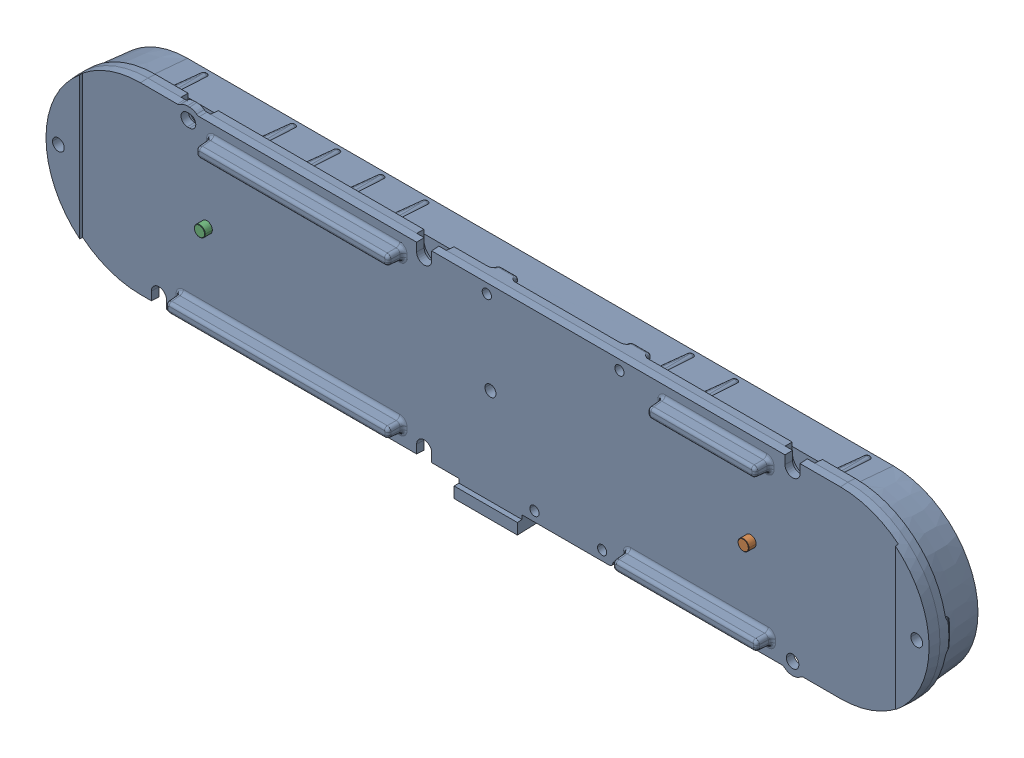
SolidWorks assembly AM0600135_ASM_3_ASM, configuration AM0600135_ASM_3_ASM. Lengths in mm.
Overall size (120.07 27.45 12.56).
3 component instances, 2 part files, 0 mates.
Components (placement in the parent):
- MEC060318_11-1: MEC060318_11 [MEC060318_11] at origin size (120.07 27.45 12.56)
- MEC060319_2-1: MEC060319_2 [MEC060319_2] at (35.3 0 -12.295) size (1.48 1.48 3)
- MEC060319_2-2: MEC060319_2 [MEC060319_2] at (-38.5 0 -12.295) size (1.48 1.48 3)
